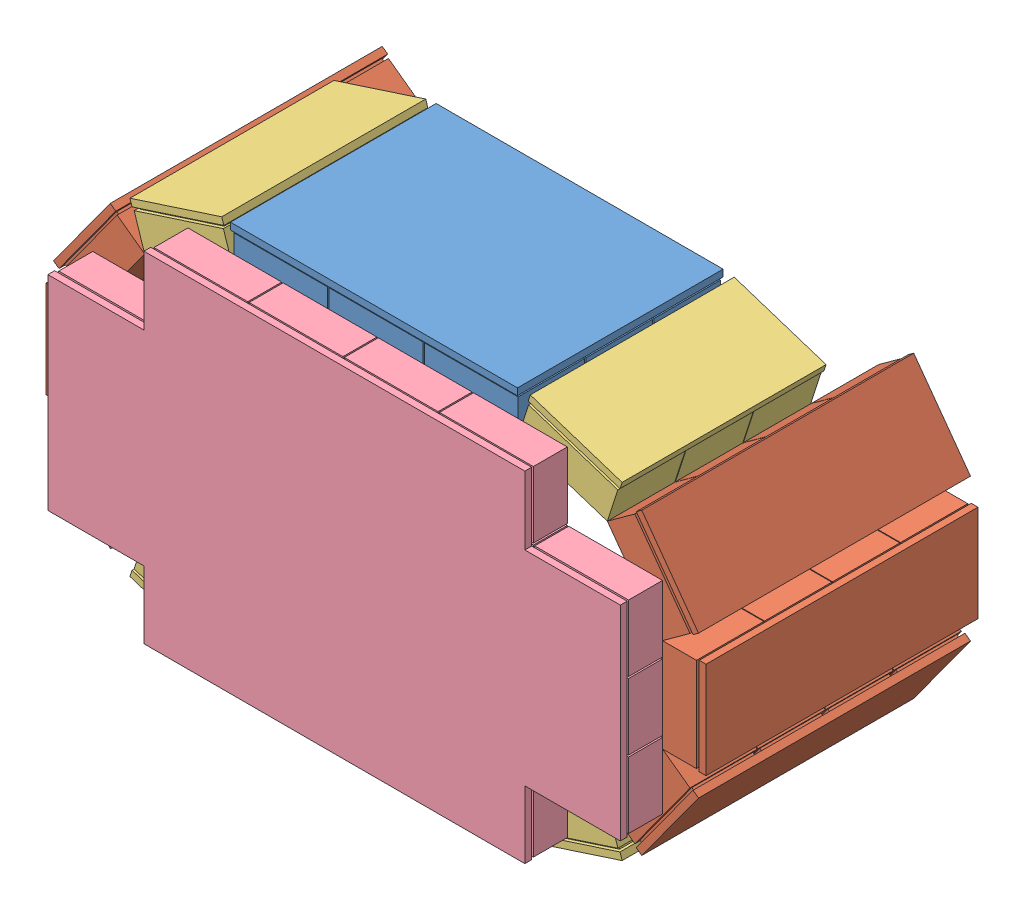
SolidWorks assembly Detector1n3_4, configuration Default. Lengths in mm.
Overall size (565.24 340.33 232).
16 component instances, 4 part files, 3 mates.
Components (placement in the parent):
- Detector1n2_3_changed-1: Detector1n2_3_changed [Default] at (-17.8211 -202.8407 225.44) size (565.24 340.33 201.48)
  - top_bottomDetector3-2: top_bottomDetector3 [Default] at (-106.7647 78.2438 -235.0736) size (211 32 151.22)
  - CshapedDetector2-3: CshapedDetector2 [Default] at (62.2764 -58.5479 -394.5758) x (0.951057 0.309017 0) z (0 0 1) size (177.89 270.84 200)
    - 1Detector-2: 1Detector [Default] at (173.0714 153.2337 184.2598) x (0.809017 0.587785 0) z (0 0 1) size (71 32 200)
    - 1Detector-4: 1Detector [Default] at (223.2683 222.3237 184.2598) x (0.309017 0.951057 0) z (0 0 1) size (71 32 200)
    - 1Detector-5: 1Detector [Default] at (223.2683 307.7237 184.2598) x (-0.309017 0.951057 0) z (0 0 1) size (71 32 200)
    - 1Detector_3modules-1: 1Detector_3modules [Default] at (91.8512 126.8436 209.2598) size (71 32 150)
    - 1Detector_3modules-2: 1Detector_3modules [Default] at (173.0714 376.8138 209.2598) x (-0.809017 0.587785 0) z (0 0 1) size (71 32 150)
  - CshapedDetector2-4: CshapedDetector2 [Default] at (-135.8058 502.3243 -394.5758) x (-0.951057 -0.309017 0) z (0 0 1) size (177.89 270.84 200)
    - 1Detector-2: 1Detector [Default] at (173.0714 153.2337 184.2598) x (0.809017 0.587785 0) z (0 0 1) size (71 32 200)
    - 1Detector-4: 1Detector [Default] at (223.2683 222.3237 184.2598) x (0.309017 0.951057 0) z (0 0 1) size (71 32 200)
    - 1Detector-5: 1Detector [Default] at (223.2683 307.7237 184.2598) x (-0.309017 0.951057 0) z (0 0 1) size (71 32 200)
    - 1Detector_3modules-1: 1Detector_3modules [Default] at (91.8512 126.8436 209.2598) size (71 32 150)
    - 1Detector_3modules-2: 1Detector_3modules [Default] at (173.0714 376.8138 209.2598) x (-0.809017 0.587785 0) z (0 0 1) size (71 32 150)
  - top_bottomDetector3-3: top_bottomDetector3 [Default] at (-106.7647 365.5325 -135.0585) x (1 0 0) z (0 0 -1) size (211 32 151.22)
- bottomDetector-1: bottomDetector [Default] at (-228.4057 17.9076 147.124) x (1 0 0) z (0 1 0) size (421 32 250)
Mates (geometry in assembly coordinates):
- Parallel1: parallel anti-aligned: line of Detector1n2_3_changed-1/top_bottomDetector3-3 through (-20.0858 130.6918 115.124) axis (-1 0 0); line of bottomDetector-1 through (-122.9057 141.92 115.124) axis (1 0 0)
- Coincident2: coincident anti-aligned: line of Detector1n2_3_changed-1/CshapedDetector2-3/1Detector-4 through (156.0943 -15.4525 115.124) axis (0 1 0); line of bottomDetector-1 through (156.0943 41.92 115.124) axis (0 -1 0)
- Distance2: distance = 14.2575 mm: line of bottomDetector-1 through (-53.9057 -106.8349 115.124) axis (-1 0 0); line of Detector1n2_3_changed-1/top_bottomDetector3-2 through (-89.0858 -92.5969 114.3788) axis (1 0 0)
